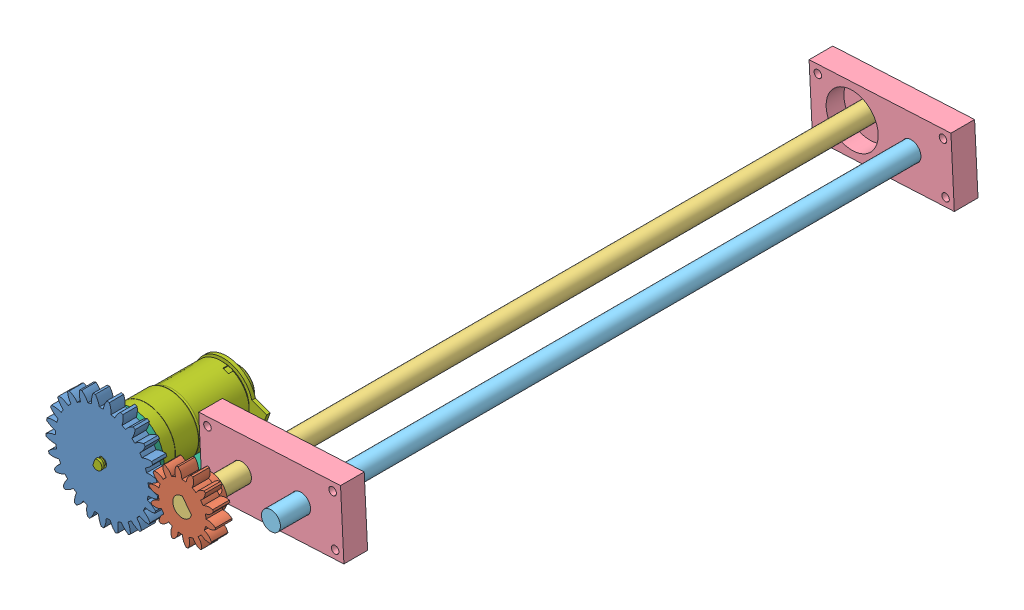
SolidWorks assembly ASCENCEURR, configuration Défaut. Lengths in mm.
Overall size (109.51 64.93 295).
8 component instances, 7 part files, 19 mates.
Components (placement in the parent):
- big gear222-1: big gear222 [Default] at (-43.9358 86.5825 -19.4311) x (0.525559 0.850757 0) z (0 0 1) size (47.21 47.12 6)
- small gear2222-1: small gear2222 [Default] at (-10.0348 87.1684 -13.4311) x (-0.293578 -0.955935 0) z (0 0 -1) size (28 27.46 12)
- tige filetee222-1: tige filetee222 [Default] at (-10.0348 87.1684 -338.4311) x (0.612614 -0.790382 0) z (0 0 1) size (8 8 293)
- jot3a guidage222222-1: jot3a guidage222222 [Default] at (2.4488 87.8079 -38.5783) x (0.99869 0.051166 0) z (0 0 -1) size (60 28 10)
- tige lisse2222-1: tige lisse2222 [Default] at (14.9324 88.4475 -358.4311) x (-0.021904 0.99976 0) z (0 0 1) size (8 8 280.5)
- jot3a guidage222222-2: jot3a guidage222222 [Default] at (2.4488 87.8079 -306.4311) x (0.99869 0.051166 0) z (0 0 1) size (60 28 10)
- support-moteur22-1: support-moteur22 [Default] at (-42.7071 67.1561 -23.4311) x (0 0 1) z (-0.99869 -0.051166 0) size (32.8 32.7 26.4)
- Motoréducteur2222-1: Motoréducteur2222 [Défaut] at (-43.9899 86.616 -42.1811) x (0 0 1) z (-0.337393 -0.941364 0) size (60.75 29.5 25)
Mates (geometry in assembly coordinates):
- Coïncidente1: coincident aligned: plane of big gear-1 through (-53.1219 81.8999 -13.4311) normal (0 0 1); plane of small gear-1 through (-7.5804 92.3744 -13.4311) normal (0 0 1)
- Contr.Engrenages2: gear = 8 : 4 mm: circle of big gear-1; circle of small gear-1
- Coïncidente2: coincident anti-aligned: plane of small gear-1 through (-9.9718 91.1679 -25.4311) normal (-0.790382 -0.612614 0); plane of tige filetee-1 through (-6.146 86.2319 -20.9311) normal (0.790382 0.612614 0)
- Coïncidente3: coincident aligned: plane of small gear-1 through (-7.5804 92.3744 -13.4311) normal (0 0 1); plane of tige filetee-1 through (-10.0348 87.1684 -13.4311) normal (0 0 1)
- Coïncidente4: coincident anti-aligned: circle of small gear-1; circle of tige filetee-1
- Coaxiale2: concentric aligned: cylinder of tige filetee-1 through (-10.0348 87.1684 -13.4311) axis (0 0 -1) radius 4; circle of jot3a guidage-1
- Coaxiale3: concentric anti-aligned: cylinder of jot3a guidage-1 through (14.9324 88.4475 -48.5783) axis (0 0 1) radius 4.1; cylinder of tige lisse-1 through (14.9324 88.4475 -70.9311) axis (0 0 -1) radius 4
- Coaxiale4: concentric aligned: cylinder of tige filetee-1 through (-10.0348 87.1684 -13.4311) axis (0 0 -1) radius 4; cylinder of jot3a guidage-2 through (-10.0348 87.1684 -296.4311) axis (0 0 -1) radius 4.1
- Coïncidente6: coincident aligned: plane of tige filetee-1 through (-10.0348 87.1684 -306.4311) normal (0 0 -1); plane of jot3a guidage-2 through (2.4488 87.8079 -306.4311) normal (0 0 -1)
- Coïncidente7: coincident aligned: plane of tige lisse-1 through (14.9324 88.4475 -306.4311) normal (0 0 -1); plane of jot3a guidage-2 through (2.4488 87.8079 -306.4311) normal (0 0 -1)
- Coaxiale5: concentric anti-aligned: circle of tige lisse-1; circle of jot3a guidage-2
- Coaxiale10: concentric aligned: circle of big gear-1; circle of support-moteur-1
- Parallèle1: parallel anti-aligned: plane of big gear-1 through (-53.1219 81.8999 -19.4311) normal (0 0 -1); plane of support-moteur-1 through (-44.3803 99.8133 -23.4311) normal (0 0 1)
- Distance1: distance = 4 mm anti-aligned: plane of big gear-1 through (-53.1219 81.8999 -19.4311) normal (0 0 -1); plane of support-moteur-1 through (-44.3803 99.8133 -23.4311) normal (0 0 1)
- Parallèle2: parallel aligned: plane of jot3a guidage-1 through (33.1258 75.3613 -48.5783) normal (0.051166 -0.99869 0); plane of support-moteur-1 through (-42.7071 67.1561 -23.4311) normal (0.051166 -0.99869 0)
- Concentric1: concentric anti-aligned: cylinder of big gear-1 through (-43.9899 86.616 -19.4311) axis (0 0 1) radius 2; cylinder of Motoréducteur-1 through (-43.9899 86.616 -47.0533) axis (0 0 -1) radius 2
- Coincident2: coincident aligned: plane of big gear-1 through (-53.1219 81.8999 -13.4311) normal (0 0 1); plane of Motoréducteur-1 through (-42.1072 85.9412 -13.4311) normal (0 0 1)
- Coincident4: coincident: line of big gear-1 through (-44.8259 88.4328 -13.4311) axis (-0.337393 -0.941364 0); plane of Motoréducteur-1 through (-47.0788 82.1472 -19.4311) normal (-0.941364 0.337393 0)
- Distance2: distance = 25.1472 mm aligned: plane of jot3a guidage-1 through (2.4488 87.8079 -38.5783) normal (0 0 1); plane of tige filetee-1 through (-10.0348 87.1684 -13.4311) normal (0 0 1)
